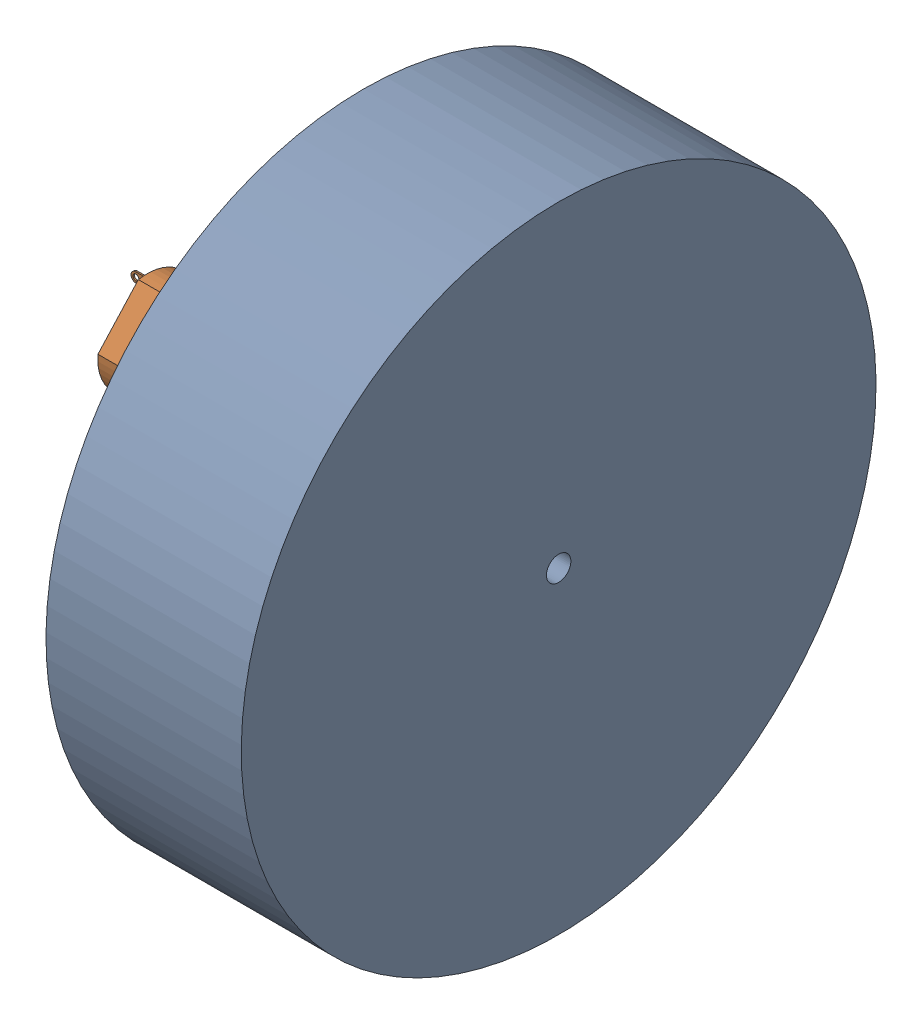
SolidWorks assembly Assem2, configuration Default. Lengths in mm.
Overall size (88.5 130 130).
2 component instances, 2 part files, 7 mates.
Components (placement in the parent):
- mockTyre-1: mockTyre [Default] at (26.0412 27.0376 55.5623) x (0 1 0) z (1 0 0) size (130 130 40)
- moto MID nap du-1: moto MID nap du [Default] at (7.0412 27.0376 55.5623) size (58.5 20.2 20.2)
Mates (geometry in assembly coordinates):
- Concentric1: concentric aligned: cylinder of Motor DC-1 through (67.7412 25.8287 57.7558) axis (1 0 0) radius 2.5; cylinder of Tyre-1 through (76.1412 17.876 47.5015) axis (1 0 0) radius 2.5
- Concentric2: concentric anti-aligned: cylinder of Motor DC-1 through (67.7412 25.8287 57.7558) axis (1 0 0) radius 2.5; cylinder of Tyre-2 through (41.0412 25.8287 57.7558) axis (-1 0 0) radius 2.5
- Distance1: distance = 0 mm anti-aligned: plane of Motor DC-1 through (26.0412 25.8287 57.7558) normal (1 0 0); plane of Tyre-2 through (26.0412 25.8287 57.7558) normal (-1 0 0)
- Concentric3: concentric anti-aligned: cylinder of Motor DC-1 through (67.7412 25.8287 57.7558) axis (1 0 0) radius 2.5; cylinder of mockTyre-1 through (66.0412 25.8287 57.7558) axis (-1 0 0) radius 2.5
- Distance2: distance = 0 mm anti-aligned: plane of mockTyre-1 through (26.0412 25.8287 57.7558) normal (-1 0 0); plane of Motor DC-1 through (26.0412 25.8287 57.7558) normal (1 0 0)
- Concentric4: concentric aligned: cylinder of mockTyre-1 through (66.0412 27.0376 55.5623) axis (-1 0 0) radius 2.5; cylinder of moto MID nap du-1 through (-14.2021 27.0376 55.5623) axis (-1 0 0) radius 2
- Coincident1: coincident anti-aligned: plane of mockTyre-1 through (26.0412 27.0376 55.5623) normal (-1 0 0); plane of moto MID nap du-1 through (4.7979 27.0376 45.5623) normal (1 0 0)
